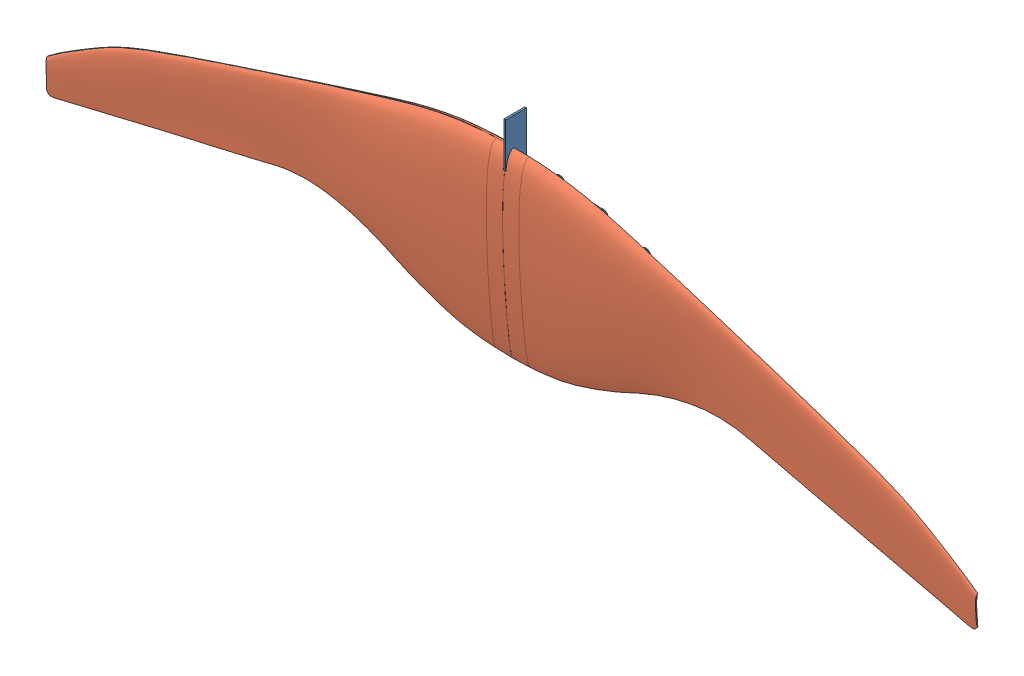
SolidWorks assembly Assem1, configuration Default. Lengths in mm.
Overall size (1558.19 358.5 53.83).
2 component instances, 2 part files, 1 mates.
Components (placement in the parent):
- Frame_structure-1: Frame_structure [Default] at (-323.2727 -187.5658 881.8049) size (442.57 350.41 45.37)
- Skin-All-1: Skin-All [Default] at (-323.4244 -187.6413 882.3689) size (1558.19 319.79 53.83)
Mates (geometry in assembly coordinates):
- Lock1: lock: unknown of Frame_structure-1; unknown of Skin-All-1
